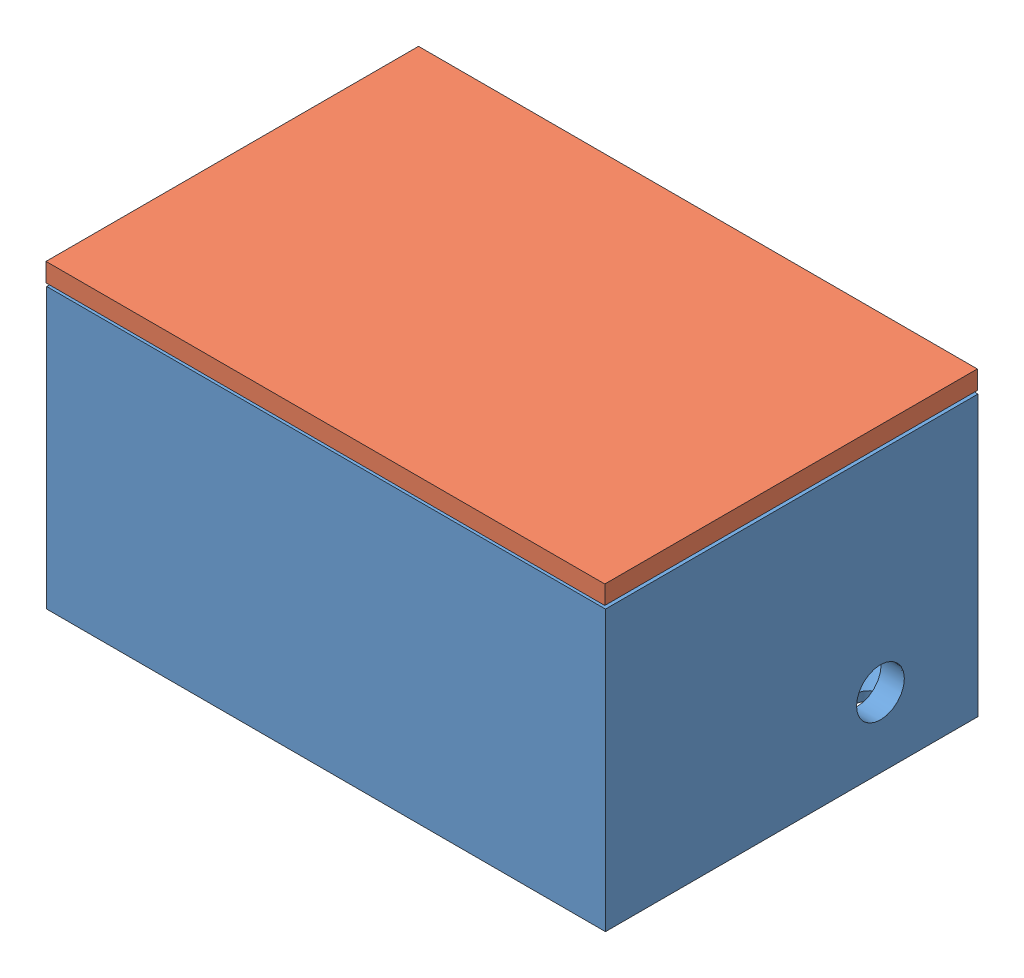
SolidWorks assembly Assem1, configuration Default. Lengths in mm.
Overall size (152.66 82.47 102.04).
2 component instances, 2 part files, 2 mates.
Components (placement in the parent):
- h1b-1: h1b [Default] at origin size (152.4 76.2 101.6)
- h1t-1: h1t [Default] at (2.3395 82.4725 -13.3012) x (-1 0 0) z (0 0 1) size (152.4 12.7 101.6)
Mates (geometry in assembly coordinates):
- Parallel3: parallel: line of h1b-1 through (-69.85 76.2 44.45) axis (1 0 0); plane of h1t-1 through (3.2583 83.5127 -10.9258) normal (0 1 0)
- Parallel4: parallel anti-aligned: line of h1b-1 through (-69.85 76.2 44.45) axis (1 0 0); line of h1t-1 through (77.3747 78.4327 53.6159) axis (-1 0 0)
